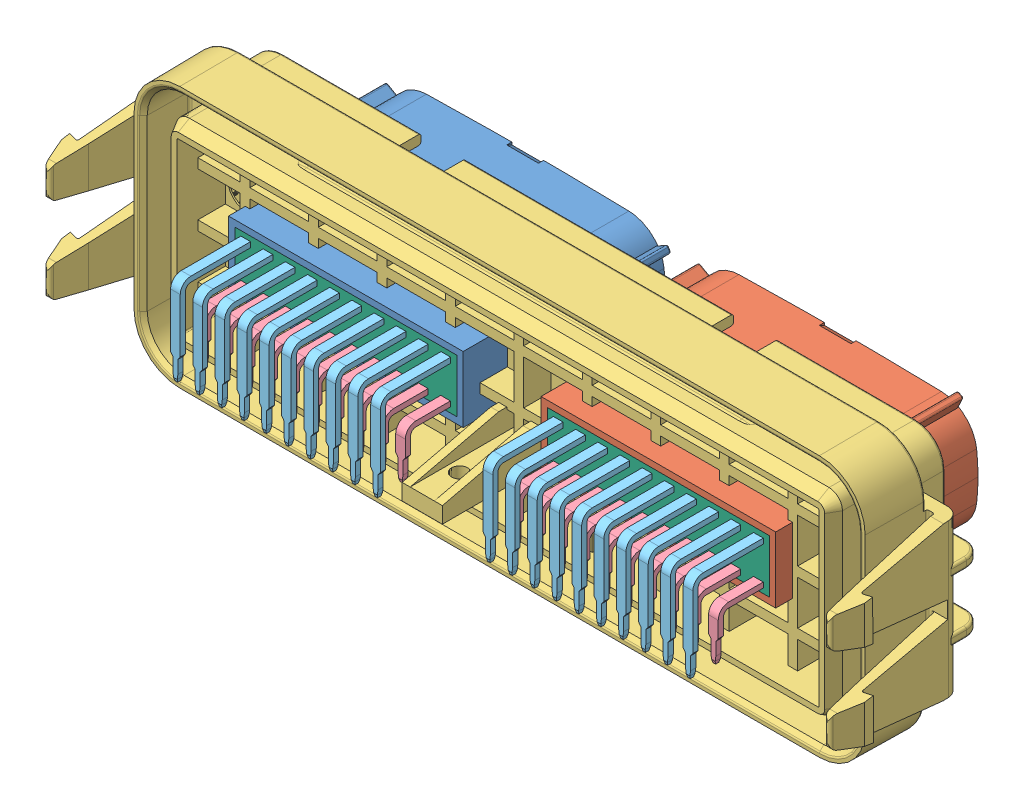
SolidWorks assembly 5810140011_model, configuration Default. Lengths in mm.
Overall size (126.6 41.34 41.26).
50 component instances, 6 part files, 0 mates.
Components (placement in the parent):
- 5810140011_model.STEP-1: 5810140011_model.STEP [Default] at origin size (126.6 41.34 41.26)
  - 5810140011_model.stp.STEP-1: 5810140011_model.stp.STEP [Default] at origin size (126.6 41.34 41.26)
    - 4828770271-ME-MX-L20B-R20A_ASM.stp.STEP-1: 4828770271-ME-MX-L20B-R20A_ASM.stp.STEP [Default] at (0 -1.143 0) x (-1 0 0) z (0 0 -1) size (126.6 41.34 41.26)
      - MOLEX-ME-A-20W_AF2_ASM.stp.STEP-1: MOLEX-ME-A-20W_AF2_ASM.stp.STEP [Default] at (24.638 1.143 0) size (47 22 28.67)
        - MOLEX-ME-A-20W_AF3.stp.STEP-1: MOLEX-ME-A-20W_AF3.stp.STEP [Default] at (-17.9886 -11.4851 -14.215) size (47 22 28.67)
      - MOLEX-ME-B-20W_AF2_ASM.stp.STEP-1: MOLEX-ME-B-20W_AF2_ASM.stp.STEP [Default] at (-24.638 1.143 0) size (47 22 28.67)
        - MOLEX-ME-B-20W_AF3.stp.STEP-1: MOLEX-ME-B-20W_AF3.stp.STEP [Default] at (-17.9886 -11.4851 -14.215) size (47 22 28.67)
      - 4741170136_MX_ME_L20B-R20A_AF1.stp.STEP-1: 4741170136_MX_ME_L20B-R20A_AF1.stp.STEP [Default] at origin size (126.6 41.34 27.94)
    - 4040011260_TYPE4.stp.STEP-1: 4040011260_TYPE4.stp.STEP [Default] at (40.4134 -3.0216 -10.4678) x (-1 0 0) z (0 0 1) size (2.54 8.02 26.57)
    - 4040011261_TYPE5.stp.STEP-1: 4040011261_TYPE5.stp.STEP [Default] at (40.4134 2.9784 -10.4678) x (-1 0 0) z (0 0 1) size (2.54 14.02 30.56)
    - 4040011260_TYPE4.stp.STEP-2: 4040011260_TYPE4.stp.STEP [Default] at (8.8626 -3.0216 -10.4678) x (-1 0 0) z (0 0 1) size (2.54 8.02 26.57)
    - 4040011261_TYPE5.stp.STEP-2: 4040011261_TYPE5.stp.STEP [Default] at (8.8626 3.0419 -10.4678) x (-1 0 0) z (0 0 1) size (2.54 14.02 30.56)
    - 4040011260_TYPE4.stp.STEP-3: 4040011260_TYPE4.stp.STEP [Default] at (-40.4134 -3.0216 -10.4678) x (-1 0 0) z (0 0 1) size (2.54 8.02 26.57)
    - 4040011261_TYPE5.stp.STEP-3: 4040011261_TYPE5.stp.STEP [Default] at (-40.4134 3.0419 -10.4678) x (-1 0 0) z (0 0 1) size (2.54 14.02 30.56)
    - 4040011260_TYPE4.stp.STEP-4: 4040011260_TYPE4.stp.STEP [Default] at (-8.9134 -2.9581 -10.4678) x (-1 0 0) z (0 0 1) size (2.54 8.02 26.57)
    - 4040011261_TYPE5.stp.STEP-4: 4040011261_TYPE5.stp.STEP [Default] at (-8.8626 3.0419 -10.4678) x (-1 0 0) z (0 0 1) size (2.54 14.02 30.56)
    - 4040011260_TYPE4.stp.STEP-5: 4040011260_TYPE4.stp.STEP [Default] at (36.8626 -3.0216 -10.4678) x (-1 0 0) z (0 0 1) size (2.54 8.02 26.57)
    - 4040011260_TYPE4.stp.STEP-6: 4040011260_TYPE4.stp.STEP [Default] at (33.3626 -3.0216 -10.4678) x (-1 0 0) z (0 0 1) size (2.54 8.02 26.57)
    - 4040011260_TYPE4.stp.STEP-7: 4040011260_TYPE4.stp.STEP [Default] at (29.8626 -3.0216 -10.4678) x (-1 0 0) z (0 0 1) size (2.54 8.02 26.57)
    - 4040011260_TYPE4.stp.STEP-8: 4040011260_TYPE4.stp.STEP [Default] at (26.3626 -3.0216 -10.4678) x (-1 0 0) z (0 0 1) size (2.54 8.02 26.57)
    - 4040011260_TYPE4.stp.STEP-9: 4040011260_TYPE4.stp.STEP [Default] at (22.8626 -3.0216 -10.4678) x (-1 0 0) z (0 0 1) size (2.54 8.02 26.57)
    - 4040011260_TYPE4.stp.STEP-10: 4040011260_TYPE4.stp.STEP [Default] at (19.3626 -3.0216 -10.4678) x (-1 0 0) z (0 0 1) size (2.54 8.02 26.57)
    - 4040011260_TYPE4.stp.STEP-11: 4040011260_TYPE4.stp.STEP [Default] at (15.8626 -3.0216 -10.4678) x (-1 0 0) z (0 0 1) size (2.54 8.02 26.57)
    - 4040011260_TYPE4.stp.STEP-12: 4040011260_TYPE4.stp.STEP [Default] at (12.3626 -3.0216 -10.4678) x (-1 0 0) z (0 0 1) size (2.54 8.02 26.57)
    - 4040011260_TYPE4.stp.STEP-13: 4040011260_TYPE4.stp.STEP [Default] at (-12.4134 -3.0216 -10.4678) x (-1 0 0) z (0 0 1) size (2.54 8.02 26.57)
    - 4040011260_TYPE4.stp.STEP-14: 4040011260_TYPE4.stp.STEP [Default] at (-15.9134 -3.0216 -10.4678) x (-1 0 0) z (0 0 1) size (2.54 8.02 26.57)
    - 4040011260_TYPE4.stp.STEP-15: 4040011260_TYPE4.stp.STEP [Default] at (-19.4134 -3.0216 -10.4678) x (-1 0 0) z (0 0 1) size (2.54 8.02 26.57)
    - 4040011260_TYPE4.stp.STEP-16: 4040011260_TYPE4.stp.STEP [Default] at (-22.9134 -3.0216 -10.4678) x (-1 0 0) z (0 0 1) size (2.54 8.02 26.57)
    - 4040011260_TYPE4.stp.STEP-17: 4040011260_TYPE4.stp.STEP [Default] at (-26.4134 -3.0216 -10.4678) x (-1 0 0) z (0 0 1) size (2.54 8.02 26.57)
    - 4040011260_TYPE4.stp.STEP-18: 4040011260_TYPE4.stp.STEP [Default] at (-29.9134 -3.0216 -10.4678) x (-1 0 0) z (0 0 1) size (2.54 8.02 26.57)
    - 4040011260_TYPE4.stp.STEP-19: 4040011260_TYPE4.stp.STEP [Default] at (-33.4134 -3.0216 -10.4678) x (-1 0 0) z (0 0 1) size (2.54 8.02 26.57)
    - 4040011260_TYPE4.stp.STEP-20: 4040011260_TYPE4.stp.STEP [Default] at (-36.9134 -3.0216 -10.4678) x (-1 0 0) z (0 0 1) size (2.54 8.02 26.57)
    - 4040011261_TYPE5.stp.STEP-5: 4040011261_TYPE5.stp.STEP [Default] at (36.8626 3.0419 -10.4678) x (-1 0 0) z (0 0 1) size (2.54 14.02 30.56)
    - 4040011261_TYPE5.stp.STEP-6: 4040011261_TYPE5.stp.STEP [Default] at (33.3626 3.0419 -10.4678) x (-1 0 0) z (0 0 1) size (2.54 14.02 30.56)
    - 4040011261_TYPE5.stp.STEP-7: 4040011261_TYPE5.stp.STEP [Default] at (29.8626 3.0419 -10.4678) x (-1 0 0) z (0 0 1) size (2.54 14.02 30.56)
    - 4040011261_TYPE5.stp.STEP-8: 4040011261_TYPE5.stp.STEP [Default] at (26.3626 3.0419 -10.4678) x (-1 0 0) z (0 0 1) size (2.54 14.02 30.56)
    - 4040011261_TYPE5.stp.STEP-9: 4040011261_TYPE5.stp.STEP [Default] at (22.8626 3.0419 -10.4678) x (-1 0 0) z (0 0 1) size (2.54 14.02 30.56)
    - 4040011261_TYPE5.stp.STEP-10: 4040011261_TYPE5.stp.STEP [Default] at (19.3626 3.0419 -10.4678) x (-1 0 0) z (0 0 1) size (2.54 14.02 30.56)
    - 4040011261_TYPE5.stp.STEP-11: 4040011261_TYPE5.stp.STEP [Default] at (15.8626 3.0419 -10.4678) x (-1 0 0) z (0 0 1) size (2.54 14.02 30.56)
    - 4040011261_TYPE5.stp.STEP-12: 4040011261_TYPE5.stp.STEP [Default] at (12.3626 3.0419 -10.4678) x (-1 0 0) z (0 0 1) size (2.54 14.02 30.56)
    - 4040011261_TYPE5.stp.STEP-13: 4040011261_TYPE5.stp.STEP [Default] at (-12.4134 3.0419 -10.4678) x (-1 0 0) z (0 0 1) size (2.54 14.02 30.56)
    - 4040011261_TYPE5.stp.STEP-14: 4040011261_TYPE5.stp.STEP [Default] at (-15.9134 3.0419 -10.4678) x (-1 0 0) z (0 0 1) size (2.54 14.02 30.56)
    - 4040011261_TYPE5.stp.STEP-15: 4040011261_TYPE5.stp.STEP [Default] at (-19.4134 3.0419 -10.4678) x (-1 0 0) z (0 0 1) size (2.54 14.02 30.56)
    - 4040011261_TYPE5.stp.STEP-16: 4040011261_TYPE5.stp.STEP [Default] at (-22.9134 3.0419 -10.4678) x (-1 0 0) z (0 0 1) size (2.54 14.02 30.56)
    - 4040011261_TYPE5.stp.STEP-17: 4040011261_TYPE5.stp.STEP [Default] at (-26.4134 3.0419 -10.4678) x (-1 0 0) z (0 0 1) size (2.54 14.02 30.56)
    - 4040011261_TYPE5.stp.STEP-18: 4040011261_TYPE5.stp.STEP [Default] at (-29.9134 3.0419 -10.4678) x (-1 0 0) z (0 0 1) size (2.54 14.02 30.56)
    - 4040011261_TYPE5.stp.STEP-19: 4040011261_TYPE5.stp.STEP [Default] at (-33.4134 3.0419 -10.4678) x (-1 0 0) z (0 0 1) size (2.54 14.02 30.56)
    - 4040011261_TYPE5.stp.STEP-20: 4040011261_TYPE5.stp.STEP [Default] at (-36.9134 3.0419 -10.4678) x (-1 0 0) z (0 0 1) size (2.54 14.02 30.56)
    - ME-MX-20W-POTTING.stp.STEP-1: ME-MX-20W-POTTING.stp.STEP [Default] at (24.638 0 9) x (1 0 0) z (0 -1 0) size (35 6.97 8.4)
    - ME-MX-20W-POTTING.stp.STEP-2: ME-MX-20W-POTTING.stp.STEP [Default] at (-24.638 0 9) x (1 0 0) z (0 -1 0) size (35 6.97 8.4)
